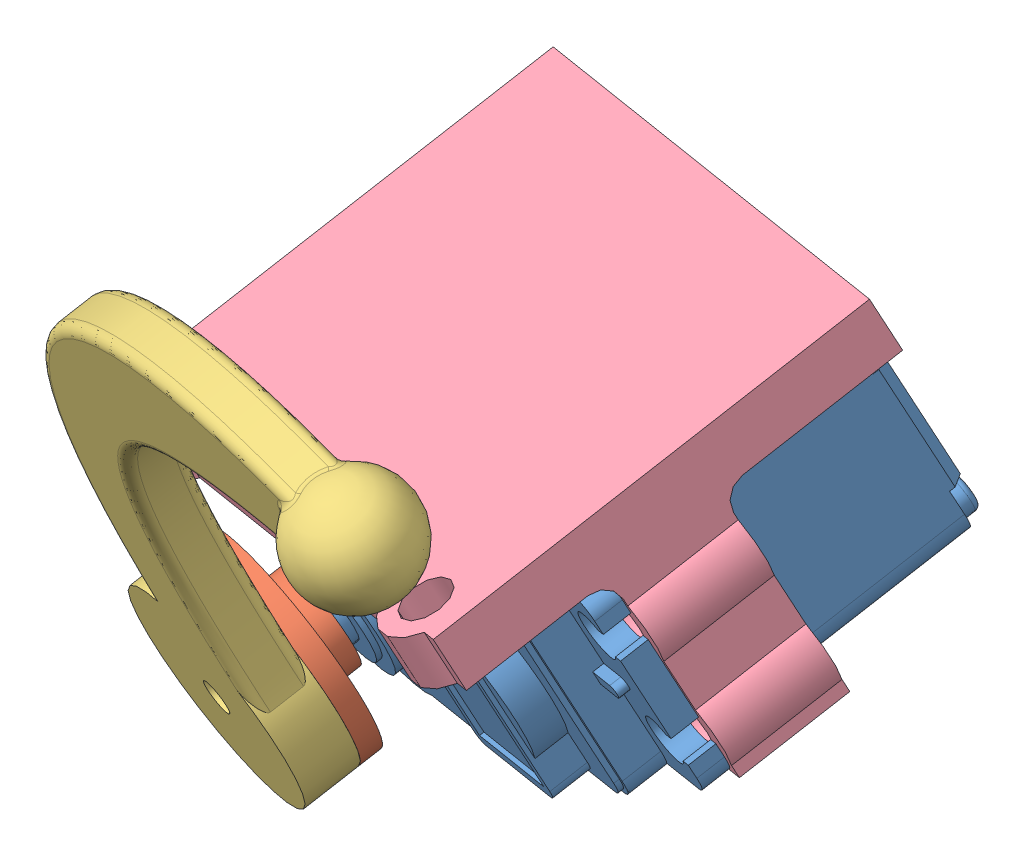
SolidWorks assembly 148, configuration Default. Lengths in mm.
Overall size (97.53 91.51 98.65).
4 component instances, 4 part files, 7 mates.
Components (placement in the parent):
- Servo-D-1: Servo-D [По умолчанию] at (85.6784 56.7652 42.3038) x (0.917218 0.220253 0.331963) z (0.331963 -0.883235 -0.331205) size (53 41.52 20)
- Access_HS-645_BrasRondPetitModele-1: Access_HS-645_BrasRondPetitModele [Défaut] at (67.9164 38.4172 73.4303) x (0.917218 0.220253 0.331963) z (0.331963 -0.883235 -0.331205) size (20 5 20)
- 200-1: 200 [Default] at (65.824 34.4843 81.8211) x (-0.668897 -0.594946 -0.445664) z (0.220253 0.413986 -0.883235) size (98.54 41.12 11)
- 160-1: 160 [Default] at (79.4405 60.1122 57.3187) x (0.917218 0.220253 0.331963) z (-0.331963 0.883235 0.331205) size (56.04 41.5 24.72)
Mates (geometry in assembly coordinates):
- Concentric1: concentric aligned: cylinder of Servo-D-1 through (67.3658 37.3822 75.6384) axis (0.220253 0.413986 -0.883235) radius 3; cylinder of Access_HS-645_BrasRondPetitModele-1 through (67.9164 38.4172 73.4303) axis (0.220253 0.413986 -0.883235) radius 2.75
- Distance1: distance = 1 mm anti-aligned: plane of Access_HS-645_BrasRondPetitModele-1 through (72.0439 39.4083 74.9242) normal (0.220253 0.413986 -0.883235); plane of Servo-D-1 through (68.1367 38.8312 72.5471) normal (-0.220253 -0.413986 0.883235)
- Concentric2: concentric anti-aligned: cylinder of Access_HS-645_BrasRondPetitModele-1 through (67.9164 38.4172 73.4303) axis (0.220253 0.413986 -0.883235) radius 10; cylinder of 200-1 through (66.9253 36.5543 77.4049) axis (-0.220253 -0.413986 0.883235) radius 10
- Coincident1: coincident anti-aligned: plane of Access_HS-645_BrasRondPetitModele-1 through (70.3648 37.3802 78.6497) normal (-0.220253 -0.413986 0.883235); plane of 200-1 through (66.9253 36.5543 77.4049) normal (0.220253 0.413986 -0.883235)
- Coincident2: coincident: plane of Servo-D-1 through (58.6907 48.1784 68.3456) normal (-0.331963 0.883235 0.331205); plane of 160-1 through (81.935 64.801 47.3153) normal (0.331963 -0.883235 -0.331205)
- Width1: width: plane of 160-1 through (58.4287 68.7557 28.3054) normal (-0.917218 -0.220253 -0.331963); plane of 160-1 through (107.9584 80.6493 46.2314) normal (0.917218 0.220253 0.331963); plane of Servo-D-1 through (62.8316 31.8397 61.72) normal (-0.917218 -0.220253 -0.331963); plane of Servo-D-1 through (99.5203 40.6498 74.9986) normal (0.917218 0.220253 0.331963)
- Coincident3: coincident anti-aligned: plane of Servo-D-1 through (54.6448 47.1475 60.0603) normal (0.220253 0.413986 -0.883235); plane of 160-1 through (50.0974 53.0963 61.7146) normal (-0.220253 -0.413986 0.883235)
